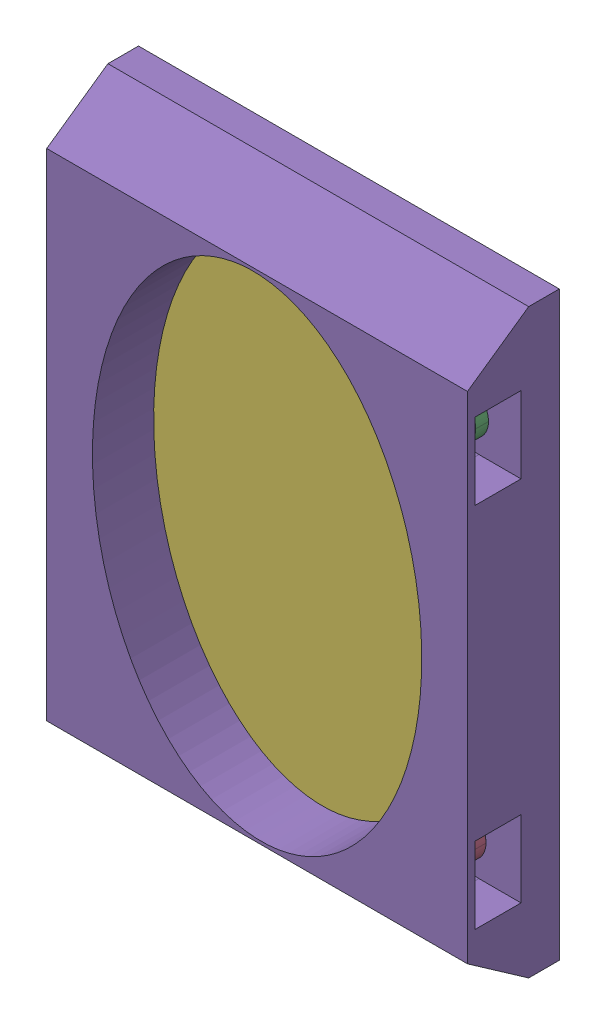
SolidWorks assembly assembly_holder_colorCombiner_dichroic_openSIM_V2.0, configuration Default. Lengths in mm.
Overall size (27.5 38 6).
6 component instances, 3 part files, 3 mates.
Components (placement in the parent):
- HXN3_1_openSIM_V2.0-1: HXN3_1_openSIM_V2.0 [Default] at (2.0711 6.3823 30.6536) x (0 0 -1) z (1 0 0) size (1 3 3)
- HXN3_1_openSIM_V2.0-2: HXN3_1_openSIM_V2.0 [Default] at (1.6489 30.6488 30.7107) x (0 0 -1) z (1 0 0) size (1 3 3)
- HXN3_1_openSIM_V2.0-3: HXN3_1_openSIM_V2.0 [Default] at (23.3423 30.7184 30.5046) x (0 0 -1) z (1 0 0) size (1 3 3)
- HXN3_1_openSIM_V2.0-4: HXN3_1_openSIM_V2.0 [Default] at (23.2779 6.8731 30.6704) x (0 0 -1) z (1 0 0) size (1 3 3)
- holder_colorCombiner_dichroic_openSIM_V2.0-1: holder_colorCombiner_dichroic_openSIM_V2.0 [Default] at (13.2217 19.0346 27.1207) x (0 1 0) z (-1 0 0) size (38 6 27.5)
- dichroicMirror_openSIM_V2.0-1: dichroicMirror_openSIM_V2.0 [Default] at (19.3529 8.9702 27.1207) x (0 -1 0) z (-1 0 0) size (35.6 2 25)
Mates (geometry in assembly coordinates):
- Coincident13: coincident anti-aligned: plane of holder_colorCombiner_dichroic_20200806-1 through (13.2217 19.0346 29.1207) normal (0 0 -1); plane of dichroicMirror_20200730-1 through (19.3529 8.9702 29.1207) normal (0 0 1)
- Coincident14: coincident anti-aligned: line of holder_colorCombiner_dichroic_20200806-1 through (0.2217 37.2846 29.1207) axis (1 0 0); line of dichroicMirror_20200730-1 through (26.2217 37.2846 29.1207) axis (-1 0 0)
- Coincident15: coincident anti-aligned: line of holder_colorCombiner_dichroic_20200806-1 through (26.2217 37.2846 29.1207) axis (0 -1 0); line of dichroicMirror_20200730-1 through (26.2217 1.6846 29.1207) axis (0 1 0)
